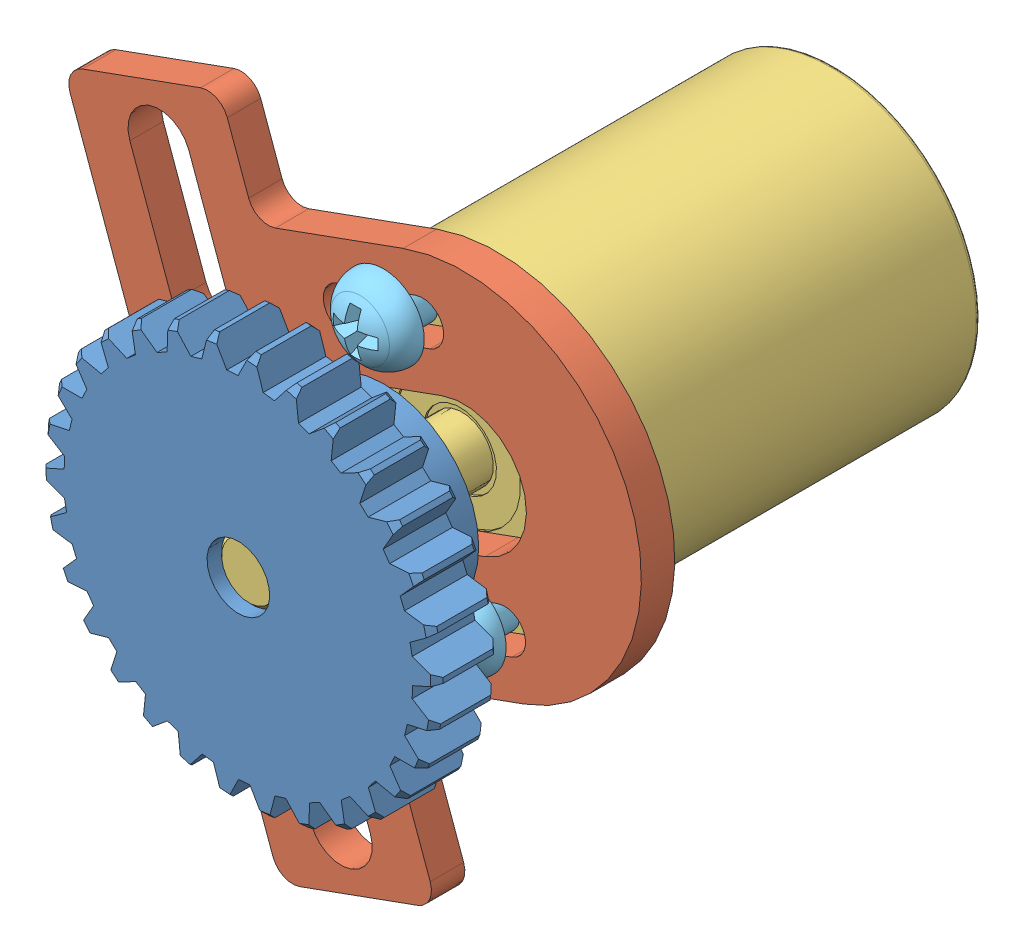
SolidWorks assembly 编码器装配体_右, configuration 默认. Lengths in mm.
Overall size (32.95 36.85 28.5).
6 component instances, 5 part files, 12 mates.
Components (placement in the parent):
- 编码器齿轮-1: 编码器齿轮 [默认] at (-11.2259 7.3482 34.8882) x (0.757709 0.652592 0) z (0 0 -1) size (18.99 18.98 7)
- 编码器支架-1: 编码器支架 [默认] at (-9.8156 7.859 25.9882) x (-0.940219 -0.340571 0) z (0 0 -1) size (24 30.5 1.6)
- 测速编码器-1: 测速编码器 [默认] at (-11.2259 7.3482 6.3882) x (0.940219 0.340571 0) z (0 0 1) size (14 14 28)
- 紧钉螺钉-M2-1: 紧钉螺钉-M2 [GB_FASTENER_SCREWS_HSCP M2X3-N] at (-9.2932 3.2844 29.8525) x (-0.429506 0.903064 0) z (0.871052 0.414281 0.263891) size (3 2 2)
- 十字半圆头螺钉-M2-1: 十字半圆头螺钉-M2 [GB_WOOD_SCREWS_TYPE136 M2X8-N] at (-9.2676 1.9419 27.5882) x (0 0 -1) z (-0.829546 -0.558439 0) size (6.56 3.9 3.9)
- 十字半圆头螺钉-M2-2: 十字半圆头螺钉-M2 [GB_WOOD_SCREWS_TYPE136 M2X8-N] at (-13.1842 12.7544 27.5882) x (0 0 -1) z (-0.999958 -0.009181 0) size (6.56 3.9 3.9)
Mates (geometry in assembly coordinates):
- 同心1: concentric anti-aligned: cylinder of 编码器齿轮-1 through (-11.2259 7.3482 31.8882) axis (0 0 1) radius 1.5; cylinder of 测速编码器-1 through (-11.2259 7.3482 34.3882) axis (0 0 -1) radius 1.5
- 距离1: distance = 0.5 mm aligned: plane of 编码器齿轮-1 through (-11.2259 7.3482 34.8882) normal (0 0 1); plane of 测速编码器-1 through (-11.2259 7.3482 34.3882) normal (0 0 1)
- 同心2: concentric aligned: cylinder of 编码器齿轮-1 through (-9.2932 3.2844 29.8525) axis (0.429506 -0.903064 0) radius 0.8; cylinder of 紧钉螺钉-M2-1 through (-2.9476 -10.0576 29.8525) axis (0.429506 -0.903064 0) radius 1
- 同心3: concentric aligned: cylinder of 编码器齿轮-1 through (-9.2932 3.2844 29.8525) axis (0.429506 -0.903064 0) radius 0.8; cylinder of 紧钉螺钉-M2-1 through (-2.9476 -10.0576 29.8525) axis (0.429506 -0.903064 0) radius 1
- 相切2: tangent anti-aligned: cylinder of 测速编码器-1 through (-11.2259 7.3482 34.3882) axis (0 0 -1) radius 1.5; plane of 紧钉螺钉-M2-1 through (-10.5817 5.9936 29.8525) normal (-0.429506 0.903064 0)
- 相切4: tangent anti-aligned: plane of 编码器支架-1 through (-7.0466 1.6828 24.3882) normal (-0.340571 0.940219 0); cylinder of 十字半圆头螺钉-M2-1 through (-9.2676 1.9419 41.2175) axis (0 0 1) radius 1
- 同心4: concentric aligned: cylinder of 测速编码器-1 through (-9.2676 1.9419 24.3882) axis (0 0 1) radius 0.8; cylinder of 十字半圆头螺钉-M2-1 through (-9.2676 1.9419 41.2175) axis (0 0 1) radius 1
- 重合5: coincident anti-aligned: plane of 编码器支架-1 through (-9.3455 8.0293 25.9882) normal (0 0 1); plane of 十字半圆头螺钉-M2-2 through (-12.1843 12.7636 25.9882) normal (0 0 -1)
- 同心5: concentric aligned: cylinder of 测速编码器-1 through (-13.1842 12.7544 24.3882) axis (0 0 1) radius 0.8; cylinder of 十字半圆头螺钉-M2-2 through (-13.1842 12.7544 41.2175) axis (0 0 1) radius 1
- 重合6: coincident anti-aligned: plane of 编码器支架-1 through (-9.3455 8.0293 24.3882) normal (0 0 -1); plane of 测速编码器-1 through (-11.2259 7.3482 24.3882) normal (0 0 1)
- 重合7: coincident anti-aligned: plane of 编码器支架-1 through (-9.3455 8.0293 25.9882) normal (0 0 1); plane of 十字半圆头螺钉-M2-1 through (-8.4381 2.5003 25.9882) normal (0 0 -1)
- 距离3: distance = 1.5 mm anti-aligned: plane of 编码器支架-1; plane of 测速编码器-1
